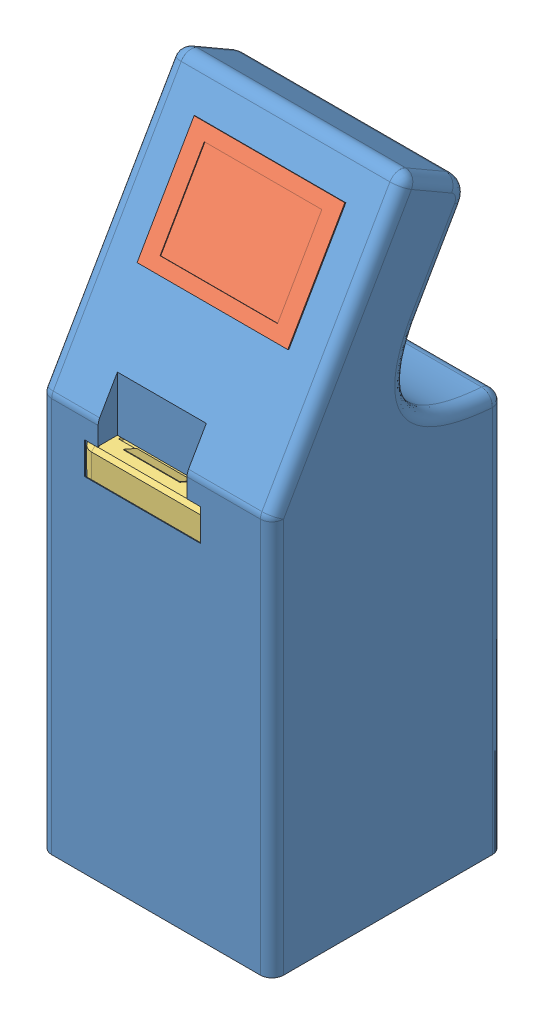
SolidWorks assembly 装配体3, configuration 默认. Lengths in mm.
Overall size (603.38 1625.24 600).
3 component instances, 3 part files, 7 mates.
Components (placement in the parent):
- 清洗机主体 导图版-1: 清洗机主体 导图版 [默认] at (25.7231 -889.7879 0) size (603.38 1625.24 600)
- 触摸屏-1: 触摸屏 [默认] at (24.7231 528.3924 79.3481) x (1 0 0) z (0 0.866025 -0.5) size (390 63 295)
- 打印机-1: 打印机 [默认] at (-27.7769 -188.2879 58.5) size (390.2 248.94 380.2)
Mates (geometry in assembly coordinates):
- 重合1: coincident anti-aligned: plane of 触摸屏-1 through (219.7231 399.1537 150.5) normal (0 -0.5 -0.866025); plane of 清洗机主体 导图版-1 through (-274.2769 140.2121 300) normal (0 0.5 0.866025)
- 距离1: distance = 1 mm anti-aligned: plane of 清洗机主体 导图版-1 through (212.2231 634.002 -19.7308) normal (-1 0 0); plane of 触摸屏-1 through (211.2231 390.6489 120.7692) normal (1 0 0)
- 距离2: distance = 1 mm anti-aligned: plane of 触摸屏-1 through (-161.7769 390.6489 120.7692) normal (0 -0.866025 0.5); plane of 清洗机主体 导图版-1 through (-160.7769 391.5149 120.2692) normal (0 0.866025 -0.5)
- 重合5: coincident anti-aligned: plane of 打印机-1 through (1067.2231 -188.2879 -131.5) normal (0 -1 0); plane of 清洗机主体 导图版-1 through (-244.2769 -188.2879 270) normal (0 1 0)
- 距离4: distance = 50 mm anti-aligned: plane of 打印机-1 through (-222.7769 61.7121 248.5) normal (0 0 1); plane of 清洗机主体 导图版-1 through (-274.2769 140.2121 298.5) normal (0 0 -1)
- 重合8: coincident anti-aligned: plane of 打印机-1 through (1067.2231 -188.2879 -131.5) normal (0 -1 0); plane of 清洗机主体 导图版-1 through (-244.2769 -188.2879 270) normal (0 1 0)
- 距离5: distance = 50 mm anti-aligned: plane of 清洗机主体 导图版-1 through (-272.7769 140.2121 -300) normal (1 0 0); plane of 打印机-1 through (-222.7769 61.7121 248.5) normal (-1 0 0)
